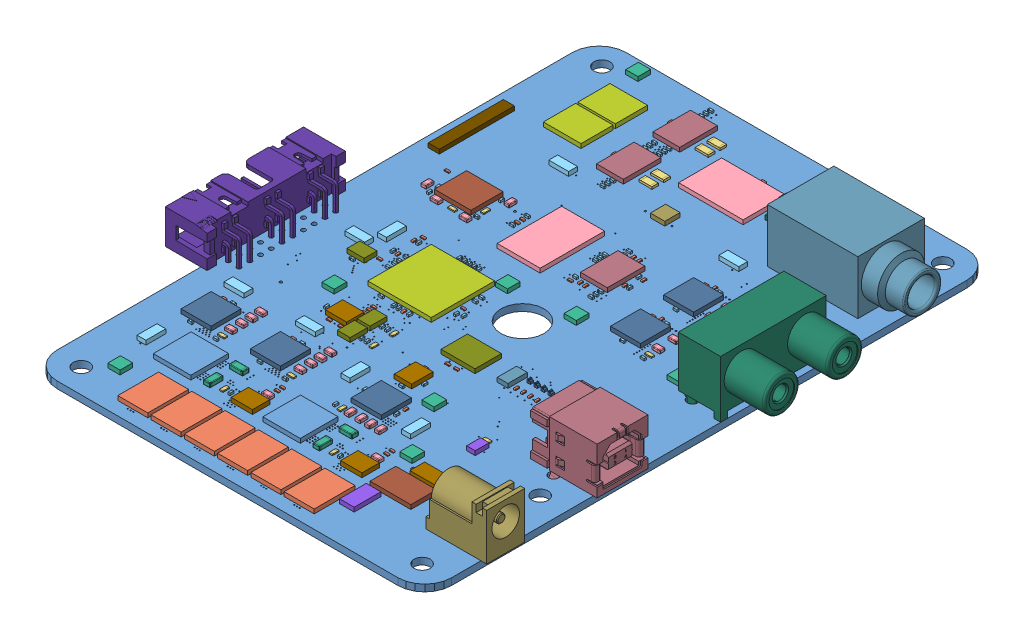
SolidWorks assembly smartstandusbdacamplifierrevb, configuration Default. Lengths in mm.
Overall size (110.75 17.47 134.62).
232 component instances, 34 part files, 16 mates.
Components (placement in the parent):
- smartstandusbdacamplifierrevb-1: smartstandusbdacamplifierrevb [Default] at origin size (93.34 1.6 134.62)
- CHEMICON_F55_CHEMICON_F55-1: CHEMICON_F55_CHEMICON_F55 [Default] at (36.83 1.6 59.309) x (0 0 1) z (0 1 0) size (9.65 7.11 1)
- CHEMICON_F55_CHEMICON_F55-2: CHEMICON_F55_CHEMICON_F55 [Default] at (52.578 1.6 59.309) x (0 0 1) z (0 1 0) size (9.65 7.11 1)
- CHEMICON_F55_CHEMICON_F55-3: CHEMICON_F55_CHEMICON_F55 [Default] at (60.452 1.6 59.309) x (0 0 1) z (0 1 0) size (9.65 7.11 1)
- CHEMICON_F55_CHEMICON_F55-4: CHEMICON_F55_CHEMICON_F55 [Default] at (28.956 1.6 59.309) x (0 0 1) z (0 1 0) size (9.65 7.11 1)
- CHEMICON_F55_CHEMICON_F55-5: CHEMICON_F55_CHEMICON_F55 [Default] at (44.704 1.6 59.309) x (0 0 1) z (0 1 0) size (9.65 7.11 1)
- CHEMICON_F55_CHEMICON_F55-6: CHEMICON_F55_CHEMICON_F55 [Default] at (21.082 1.6 59.309) x (0 0 1) z (0 1 0) size (9.65 7.11 1)
- C0603-1: C0603 [Default] at (69.596 1.6 28.829) x (-1 0 0) z (0 1 0) size (1.6 0.8 0.3)
- C0603-2: C0603 [Default] at (27.94 1.6 49.276) x (0 0 -1) z (0 1 0) size (1.6 0.8 0.3)
- C0603-3: C0603 [Default] at (33.147 1.6 38.608) x (1 0 0) z (0 1 0) size (1.6 0.8 0.3)
- C0603-4: C0603 [Default] at (53.848 1.6 49.276) x (0 0 -1) z (0 1 0) size (1.6 0.8 0.3)
- C0603-5: C0603 [Default] at (45.847 1.6 39.37) x (0 0 1) z (0 1 0) size (1.6 0.8 0.3)
- C0603-6: C0603 [Default] at (16.764 1.6 38.608) x (1 0 0) z (0 1 0) size (1.6 0.8 0.3)
- C0603-7: C0603 [Default] at (71.247 1.6 -8.001) x (1 0 0) z (0 1 0) size (1.6 0.8 0.3)
- C0603-8: C0603 [Default] at (71.247 1.6 -15.875) x (1 0 0) z (0 1 0) size (1.6 0.8 0.3)
- C0603-9: C0603 [Default] at (71.12 1.6 -20.701) x (1 0 0) z (0 1 0) size (1.6 0.8 0.3)
- C0603-10: C0603 [Default] at (71.12 1.6 -28.575) x (1 0 0) z (0 1 0) size (1.6 0.8 0.3)
- C0603-11: C0603 [Default] at (18.034 1.6 -14.605) x (-1 0 0) z (0 1 0) size (1.6 0.8 0.3)
- C0603-12: C0603 [Default] at (22.352 1.6 -18.034) x (0 0 1) z (0 1 0) size (1.6 0.8 0.3)
- C0603-13: C0603 [Default] at (36.703 1.6 22.733) x (0 0 -1) z (0 1 0) size (1.6 0.8 0.3)
- C0603-14: C0603 [Default] at (36.703 1.6 17.907) x (0 0 -1) z (0 1 0) size (1.6 0.8 0.3)
- C0805-1: C0805 [Default] at (34.544 1.6 45.593) x (-1 0 0) z (0 1 0) size (2 1.25 0.78)
- C0805-2: C0805 [Default] at (33.147 1.6 36.576) x (1 0 0) z (0 1 0) size (2 1.25 0.78)
- C0805-3: C0805 [Default] at (33.147 1.6 34.036) x (1 0 0) z (0 1 0) size (2 1.25 0.78)
- C0805-4: C0805 [Default] at (33.147 1.6 31.75) x (1 0 0) z (0 1 0) size (2 1.25 0.78)
- C0805-5: C0805 [Default] at (33.147 1.6 29.464) x (1 0 0) z (0 1 0) size (2 1.25 0.78)
- C0805-6: C0805 [Default] at (60.452 1.6 45.593) x (-1 0 0) z (0 1 0) size (2 1.25 0.78)
- C0805-7: C0805 [Default] at (47.879 1.6 39.37) x (0 0 1) z (0 1 0) size (2 1.25 0.78)
- C0805-8: C0805 [Default] at (54.991 1.6 39.37) x (0 0 1) z (0 1 0) size (2 1.25 0.78)
- C0805-9: C0805 [Default] at (52.705 1.6 39.37) x (0 0 1) z (0 1 0) size (2 1.25 0.78)
- C0805-10: C0805 [Default] at (50.419 1.6 39.37) x (0 0 1) z (0 1 0) size (2 1.25 0.78)
- C0805-11: C0805 [Default] at (16.764 1.6 36.576) x (1 0 0) z (0 1 0) size (2 1.25 0.78)
- C0805-12: C0805 [Default] at (16.764 1.6 34.036) x (1 0 0) z (0 1 0) size (2 1.25 0.78)
- C0805-13: C0805 [Default] at (16.764 1.6 31.75) x (1 0 0) z (0 1 0) size (2 1.25 0.78)
- C0805-14: C0805 [Default] at (16.764 1.6 29.464) x (1 0 0) z (0 1 0) size (2 1.25 0.78)
- C0805-15: C0805 [Default] at (71.247 1.6 -10.033) x (1 0 0) z (0 1 0) size (2 1.25 0.78)
- C0805-16: C0805 [Default] at (71.247 1.6 -13.843) x (1 0 0) z (0 1 0) size (2 1.25 0.78)
- C0805-17: C0805 [Default] at (71.12 1.6 -22.733) x (1 0 0) z (0 1 0) size (2 1.25 0.78)
- C0805-18: C0805 [Default] at (71.12 1.6 -26.543) x (1 0 0) z (0 1 0) size (2 1.25 0.78)
- C0805-19: C0805 [Default] at (10.16 1.6 -16.51) x (0 0 1) z (0 1 0) size (2 1.25 0.78)
- C0805-20: C0805 [Default] at (21.59 1.6 -14.097) x (1 0 0) z (0 1 0) size (2 1.25 0.78)
- C0805-21: C0805 [Default] at (14.478 1.6 -14.351) x (1 0 0) z (0 1 0) size (2 1.25 0.78)
- C0805-22: C0805 [Default] at (23.876 1.6 -22.479) x (0 0 -1) z (0 1 0) size (2 1.25 0.78)
- C0402-1: C0402 [Default] at (27.94 1.6 30.861) x (-1 0 0) z (0 1 0) size (1 0.5 0.5)
- C0402-2: C0402 [Default] at (29.591 1.6 49.403) x (0 0 -1) z (0 1 0) size (1 0.5 0.5)
- C0402-3: C0402 [Default] at (33.147 1.6 40.132) x (1 0 0) z (0 1 0) size (1 0.5 0.5)
- C0402-4: C0402 [Default] at (26.67 1.6 39.624) x (-1 0 0) z (0 1 0) size (1 0.5 0.5)
- C0402-5: C0402 [Default] at (53.594 1.6 34.163) x (0 0 -1) z (0 1 0) size (1 0.5 0.5)
- C0402-6: C0402 [Default] at (55.499 1.6 49.403) x (0 0 -1) z (0 1 0) size (1 0.5 0.5)
- C0402-7: C0402 [Default] at (44.323 1.6 39.37) x (0 0 1) z (0 1 0) size (1 0.5 0.5)
- C0402-8: C0402 [Default] at (44.831 1.6 32.893) x (0 0 -1) z (0 1 0) size (1 0.5 0.5)
- C0402-9: C0402 [Default] at (11.557 1.6 30.861) x (-1 0 0) z (0 1 0) size (1 0.5 0.5)
- C0402-10: C0402 [Default] at (16.764 1.6 40.132) x (1 0 0) z (0 1 0) size (1 0.5 0.5)
- C0402-11: C0402 [Default] at (10.287 1.6 39.624) x (-1 0 0) z (0 1 0) size (1 0.5 0.5)
- C0402-12: C0402 [Default] at (67.056 1.6 -16.256) x (-1 0 0) z (0 1 0) size (1 0.5 0.5)
- C0402-13: C0402 [Default] at (71.247 1.6 -6.477) x (1 0 0) z (0 1 0) size (1 0.5 0.5)
- C0402-14: C0402 [Default] at (71.247 1.6 -17.399) x (1 0 0) z (0 1 0) size (1 0.5 0.5)
- C0402-15: C0402 [Default] at (65.278 1.6 -7.62) x (-1 0 0) z (0 1 0) size (1 0.5 0.5)
- C0402-16: C0402 [Default] at (66.929 1.6 -28.956) x (-1 0 0) z (0 1 0) size (1 0.5 0.5)
- C0402-17: C0402 [Default] at (71.12 1.6 -19.177) x (1 0 0) z (0 1 0) size (1 0.5 0.5)
- C0402-18: C0402 [Default] at (71.12 1.6 -30.099) x (1 0 0) z (0 1 0) size (1 0.5 0.5)
- C0402-19: C0402 [Default] at (65.151 1.6 -20.32) x (-1 0 0) z (0 1 0) size (1 0.5 0.5)
- C0402-20: C0402 [Default] at (50.673 1.6 24.638) x (0 0 -1) z (0 1 0) size (1 0.5 0.5)
- C0402-21: C0402 [Default] at (48.387 1.6 27.813) x (1 0 0) z (0 1 0) size (1 0.5 0.5)
- C0402-22: C0402 [Default] at (22.479 1.6 3.556) x (-1 0 0) z (0 1 0) size (1 0.5 0.5)
- C0402-23: C0402 [Default] at (32.131 1.6 12.192) x (0 0 1) z (0 1 0) size (1 0.5 0.5)
- C0402-24: C0402 [Default] at (40.132 1.6 6.604) x (0 0 1) z (0 1 0) size (1 0.5 0.5)
- C0402-25: C0402 [Default] at (39.751 1.6 1.778) x (1 0 0) z (0 1 0) size (1 0.5 0.5)
- C0402-26: C0402 [Default] at (22.479 1.6 5.08) x (-1 0 0) z (0 1 0) size (1 0.5 0.5)
- C0402-27: C0402 [Default] at (30.988 1.6 12.192) x (0 0 1) z (0 1 0) size (1 0.5 0.5)
- C0402-28: C0402 [Default] at (32.512 1.6 -5.207) x (0 0 -1) z (0 1 0) size (1 0.5 0.5)
- C0402-29: C0402 [Default] at (31.369 1.6 -5.207) x (0 0 -1) z (0 1 0) size (1 0.5 0.5)
- C0402-30: C0402 [Default] at (30.226 1.6 -5.207) x (0 0 -1) z (0 1 0) size (1 0.5 0.5)
- C0402-31: C0402 [Default] at (22.479 1.6 0.889) x (-1 0 0) z (0 1 0) size (1 0.5 0.5)
- C0402-32: C0402 [Default] at (39.751 1.6 0.254) x (1 0 0) z (0 1 0) size (1 0.5 0.5)
- C0402-33: C0402 [Default] at (29.083 1.6 -5.207) x (0 0 -1) z (0 1 0) size (1 0.5 0.5)
- C0402-34: C0402 [Default] at (33.655 1.6 -5.207) x (0 0 -1) z (0 1 0) size (1 0.5 0.5)
- C0402-35: C0402 [Default] at (22.479 1.6 2.413) x (-1 0 0) z (0 1 0) size (1 0.5 0.5)
- C0402-36: C0402 [Default] at (41.402 1.6 6.096) x (0 0 1) z (0 1 0) size (1 0.5 0.5)
- C0402-37: C0402 [Default] at (27.559 1.6 11.811) x (-1 0 0) z (0 1 0) size (1 0.5 0.5)
- C0402-38: C0402 [Default] at (34.671 1.6 12.192) x (0 0 1) z (0 1 0) size (1 0.5 0.5)
- C0402-39: C0402 [Default] at (16.51 1.6 7.62) x (-1 0 0) z (0 1 0) size (1 0.5 0.5)
- C0402-40: C0402 [Default] at (19.685 1.6 1.143) x (0 0 -1) z (0 1 0) size (1 0.5 0.5)
- C0402-41: C0402 [Default] at (11.938 1.6 -17.272) x (0 0 1) z (0 1 0) size (1 0.5 0.5)
- C0402-42: C0402 [Default] at (28.448 1.6 -18.288) x (-1 0 0) z (0 1 0) size (1 0.5 0.5)
- C0402-43: C0402 [Default] at (28.448 1.6 -21.844) x (-1 0 0) z (0 1 0) size (1 0.5 0.5)
- C0402-44: C0402 [Default] at (22.606 1.6 -15.748) x (1 0 0) z (0 1 0) size (1 0.5 0.5)
- C0402-45: C0402 [Default] at (11.938 1.6 -15.24) x (0 0 1) z (0 1 0) size (1 0.5 0.5)
- C0402-46: C0402 [Default] at (22.098 1.6 -22.098) x (0 0 -1) z (0 1 0) size (1 0.5 0.5)
- C0402-47: C0402 [Default] at (46.609 1.6 -15.113) x (-1 0 0) z (0 1 0) size (1 0.5 0.5)
- C0402-48: C0402 [Default] at (55.245 1.6 -19.304) x (0 0 1) z (0 1 0) size (1 0.5 0.5)
- C0402-49: C0402 [Default] at (47.752 1.6 -26.67) x (-1 0 0) z (0 1 0) size (1 0.5 0.5)
- C0402-50: C0402 [Default] at (54.102 1.6 -22.606) x (0 0 -1) z (0 1 0) size (1 0.5 0.5)
- C0402-51: C0402 [Default] at (52.578 1.6 -12.827) x (1 0 0) z (0 1 0) size (1 0.5 0.5)
- C0402-52: C0402 [Default] at (52.578 1.6 -13.97) x (1 0 0) z (0 1 0) size (1 0.5 0.5)
- C0402-53: C0402 [Default] at (52.578 1.6 -15.113) x (1 0 0) z (0 1 0) size (1 0.5 0.5)
- C0402-54: C0402 [Default] at (45.593 1.6 -23.114) x (-1 0 0) z (0 1 0) size (1 0.5 0.5)
- C0402-55: C0402 [Default] at (45.593 1.6 -21.971) x (-1 0 0) z (0 1 0) size (1 0.5 0.5)
- C0402-56: C0402 [Default] at (45.593 1.6 -20.828) x (-1 0 0) z (0 1 0) size (1 0.5 0.5)
- C0402-57: C0402 [Default] at (28.575 1.6 -65.151) x (1 0 0) z (0 1 0) size (1 0.5 0.5)
- C0402-58: C0402 [Default] at (28.575 1.6 -64.008) x (1 0 0) z (0 1 0) size (1 0.5 0.5)
- C0402-59: C0402 [Default] at (28.575 1.6 -62.865) x (1 0 0) z (0 1 0) size (1 0.5 0.5)
- C0402-60: C0402 [Default] at (28.448 1.6 -51.943) x (1 0 0) z (0 1 0) size (1 0.5 0.5)
- C0402-61: C0402 [Default] at (28.448 1.6 -50.8) x (1 0 0) z (0 1 0) size (1 0.5 0.5)
- C0402-62: C0402 [Default] at (28.448 1.6 -49.657) x (1 0 0) z (0 1 0) size (1 0.5 0.5)
- C0402-63: C0402 [Default] at (31.369 1.6 -50.165) x (-1 0 0) z (0 1 0) size (1 0.5 0.5)
- C0402-64: C0402 [Default] at (31.369 1.6 -51.308) x (-1 0 0) z (0 1 0) size (1 0.5 0.5)
- C0402-65: C0402 [Default] at (31.369 1.6 -52.451) x (-1 0 0) z (0 1 0) size (1 0.5 0.5)
- C0402-66: C0402 [Default] at (31.242 1.6 -36.957) x (-1 0 0) z (0 1 0) size (1 0.5 0.5)
- C0402-67: C0402 [Default] at (31.242 1.6 -38.1) x (-1 0 0) z (0 1 0) size (1 0.5 0.5)
- C0402-68: C0402 [Default] at (31.242 1.6 -39.243) x (-1 0 0) z (0 1 0) size (1 0.5 0.5)
- C0402-69: C0402 [Default] at (35.179 1.6 22.733) x (0 0 -1) z (0 1 0) size (1 0.5 0.5)
- C0402-70: C0402 [Default] at (33.909 1.6 22.733) x (0 0 -1) z (0 1 0) size (1 0.5 0.5)
- C0402-71: C0402 [Default] at (35.179 1.6 17.907) x (0 0 -1) z (0 1 0) size (1 0.5 0.5)
- C0402-72: C0402 [Default] at (33.909 1.6 17.907) x (0 0 -1) z (0 1 0) size (1 0.5 0.5)
- C0402-73: C0402 [Default] at (23.241 1.6 20.447) x (0 0 1) z (0 1 0) size (1 0.5 0.5)
- C0402-74: C0402 [Default] at (21.082 1.6 -3.556) x (0 0 -1) z (0 1 0) size (1 0.5 0.5)
- C1206-1: C1206 [Default] at (25.146 1.6 49.149) x (0 0 -1) z (0 1 0) size (3.2 1.6 1)
- C1206-2: C1206 [Default] at (25.781 1.6 43.688) x (1 0 0) z (0 1 0) size (3.2 1.6 1)
- C1206-3: C1206 [Default] at (51.054 1.6 49.149) x (0 0 -1) z (0 1 0) size (3.2 1.6 1)
- C1206-4: C1206 [Default] at (51.689 1.6 43.688) x (1 0 0) z (0 1 0) size (3.2 1.6 1)
- KEMET5MM6_07_2_KEMET5MM6_07_2-1: KEMET5MM6_07_2_KEMET5MM6_07_2 [Default] at (16.256 1.6 -54.229) x (1 0 0) z (0 1 0) size (8.89 7.62 1)
- KEMET5MM6_07_2_KEMET5MM6_07_2-2: KEMET5MM6_07_2_KEMET5MM6_07_2 [Default] at (16.256 1.6 -46.101) x (1 0 0) z (0 1 0) size (8.89 7.62 1)
- SOD128_5A-1: SOD128_5A [Default] at (66.675 1.6 55.88) x (0 0 -1) z (0 1 0) size (6.33 3.46 1)
- SMA_13_6V-1: SMA_13_6V [Default] at (70.993 1.6 43.18) x (-1 0 0) z (0 1 0) size (7.1 3.5 1)
- DIALIGHT-0603-1: DIALIGHT-0603 [Default] at (62.357 1.6 11.684) x (0 0 1) z (0 1 0) size (0.79 0.72 1.63)
- DIALIGHT-0603-2: DIALIGHT-0603 [Default] at (68.961 1.6 11.684) x (0 0 1) z (0 1 0) size (0.79 0.72 1.63)
- DIALIGHT-0603-3: DIALIGHT-0603 [Default] at (70.612 1.6 11.684) x (0 0 1) z (0 1 0) size (0.79 0.72 1.63)
- DIALIGHT-0603-4: DIALIGHT-0603 [Default] at (67.31 1.6 11.684) x (0 0 1) z (0 1 0) size (0.79 0.72 1.63)
- DIALIGHT-0603-5: DIALIGHT-0603 [Default] at (65.659 1.6 11.684) x (0 0 1) z (0 1 0) size (0.79 0.72 1.63)
- DIALIGHT-0603-6: DIALIGHT-0603 [Default] at (64.008 1.6 11.684) x (0 0 1) z (0 1 0) size (0.79 0.72 1.63)
- 2920L_0_6A-1: 2920L_0_6A [Default] at (69.723 1.6 48.768) x (-1 0 0) z (0 1 0) size (9.65 6.1 1)
- PJ002A_PJ002A-1: PJ002A_PJ002A [Default] at (94.695 8.1 49.51) size (14.4 14.5 9.4)
- 292304-1: 292304 [Default] at (94.665 7.29 21.844) x (0 0 -1) z (1 0 0) size (14.36 15.42 15.7)
- NRJ6HH_NRJ6HH-1: NRJ6HH_NRJ6HH [Default] at (88.32 1.6 -46.61) x (0 0 -1) z (1 0 0) size (15.75 16.7 33.2)
- PJRAN2X1U01AUX-1: PJRAN2X1U01AUX [Default] at (88.289 9.0803 -15.2344) x (0 0 -1) z (0 -1 0) size (25 19.5 17.47)
- T1MSINGLE5POS_T1M5POS-1: T1MSINGLE5POS_T1M5POS [Default] at (50.292 1.6 12.573) x (1 0 0) z (0 1 0) size (8.03 6.25 1)
- N2520-5002-1: N2520-5002 [Default] at (1.4342 7.3912 28.8324) x (0 1 0) z (-1 0 0) size (12.62 32.72 12.87)
- 1X07_JP3_1X07-1: 1X07_JP3_1X07 [Default] at (3.81 1.6 -33.274) x (0 0 -1) z (1 0 0) size (17.78 1 2.62)
- TDKVLP8040_TDKVLP8040-1: TDKVLP8040_TDKVLP8040 [Default] at (17.526 1.6 46.863) x (0 0 1) z (0 1 0) size (8.93 8.86 1)
- TDKVLP8040_TDKVLP8040-2: TDKVLP8040_TDKVLP8040 [Default] at (43.434 1.6 46.863) x (0 0 1) z (0 1 0) size (8.93 8.86 1)
- R0402-1: R0402 [Default] at (39.751 1.6 4.572) x (-1 0 0) z (0 1 0) size (1.01 0.5 0.32)
- R0402-2: R0402 [Default] at (25.781 1.6 30.861) x (-1 0 0) z (0 1 0) size (1.01 0.5 0.32)
- R0402-3: R0402 [Default] at (34.544 1.6 42.164) x (-1 0 0) z (0 1 0) size (1.01 0.5 0.32)
- R0402-4: R0402 [Default] at (34.544 1.6 43.434) x (1 0 0) z (0 1 0) size (1.01 0.5 0.32)
- R0402-5: R0402 [Default] at (53.594 1.6 32.004) x (0 0 -1) z (0 1 0) size (1.01 0.5 0.32)
- R0402-6: R0402 [Default] at (60.452 1.6 42.164) x (-1 0 0) z (0 1 0) size (1.01 0.5 0.32)
- R0402-7: R0402 [Default] at (60.452 1.6 43.434) x (1 0 0) z (0 1 0) size (1.01 0.5 0.32)
- R0402-8: R0402 [Default] at (9.398 1.6 30.861) x (-1 0 0) z (0 1 0) size (1.01 0.5 0.32)
- R0402-9: R0402 [Default] at (65.405 1.6 -16.637) x (0 0 -1) z (0 1 0) size (1.01 0.5 0.32)
- R0402-10: R0402 [Default] at (63.754 1.6 -16.256) x (1 0 0) z (0 1 0) size (1.01 0.5 0.32)
- R0402-11: R0402 [Default] at (65.278 1.6 -29.337) x (0 0 -1) z (0 1 0) size (1.01 0.5 0.32)
- R0402-12: R0402 [Default] at (63.627 1.6 -28.956) x (1 0 0) z (0 1 0) size (1.01 0.5 0.32)
- R0402-13: R0402 [Default] at (47.498 1.6 21.209) x (1 0 0) z (0 1 0) size (1.01 0.5 0.32)
- R0402-14: R0402 [Default] at (20.828 1.6 1.143) x (0 0 -1) z (0 1 0) size (1.01 0.5 0.32)
- R0402-15: R0402 [Default] at (19.685 1.6 4.318) x (1 0 0) z (0 1 0) size (1.01 0.5 0.32)
- R0402-16: R0402 [Default] at (33.274 1.6 12.192) x (0 0 1) z (0 1 0) size (1.01 0.5 0.32)
- R0402-17: R0402 [Default] at (51.308 1.6 17.78) x (1 0 0) z (0 1 0) size (1.01 0.5 0.32)
- R0402-18: R0402 [Default] at (49.276 1.6 17.78) x (-1 0 0) z (0 1 0) size (1.01 0.5 0.32)
- R0402-19: R0402 [Default] at (28.829 1.6 14.859) x (-1 0 0) z (0 1 0) size (1.01 0.5 0.32)
- R0402-20: R0402 [Default] at (28.829 1.6 16.002) x (-1 0 0) z (0 1 0) size (1.01 0.5 0.32)
- R0402-21: R0402 [Default] at (9.652 1.6 -21.717) x (-1 0 0) z (0 1 0) size (1.01 0.5 0.32)
- R0402-22: R0402 [Default] at (28.448 1.6 -19.431) x (1 0 0) z (0 1 0) size (1.01 0.5 0.32)
- R0402-23: R0402 [Default] at (28.448 1.6 -20.701) x (1 0 0) z (0 1 0) size (1.01 0.5 0.32)
- R0402-24: R0402 [Default] at (48.26 1.6 -14.605) x (0 0 -1) z (0 1 0) size (1.01 0.5 0.32)
- R0402-25: R0402 [Default] at (46.609 1.6 -13.843) x (1 0 0) z (0 1 0) size (1.01 0.5 0.32)
- R0402-26: R0402 [Default] at (54.102 1.6 -19.304) x (0 0 1) z (0 1 0) size (1.01 0.5 0.32)
- R0402-27: R0402 [Default] at (49.403 1.6 -26.035) x (0 0 1) z (0 1 0) size (1.01 0.5 0.32)
- R0402-28: R0402 [Default] at (47.752 1.6 -25.527) x (1 0 0) z (0 1 0) size (1.01 0.5 0.32)
- R0402-29: R0402 [Default] at (55.245 1.6 -22.606) x (0 0 -1) z (0 1 0) size (1.01 0.5 0.32)
- R0402-30: R0402 [Default] at (49.53 1.6 -14.605) x (0 0 1) z (0 1 0) size (1.01 0.5 0.32)
- R0402-31: R0402 [Default] at (50.8 1.6 -26.035) x (0 0 1) z (0 1 0) size (1.01 0.5 0.32)
- R0402-32: R0402 [Default] at (26.035 1.6 -58.166) x (0 0 1) z (0 1 0) size (1.01 0.5 0.32)
- R0402-33: R0402 [Default] at (25.908 1.6 -44.958) x (0 0 1) z (0 1 0) size (1.01 0.5 0.32)
- R0402-34: R0402 [Default] at (28.829 1.6 22.733) x (1 0 0) z (0 1 0) size (1.01 0.5 0.32)
- R0402-35: R0402 [Default] at (28.829 1.6 17.145) x (1 0 0) z (0 1 0) size (1.01 0.5 0.32)
- R0402-36: R0402 [Default] at (26.162 1.6 22.733) x (-1 0 0) z (0 1 0) size (1.01 0.5 0.32)
- R0402-37: R0402 [Default] at (20.447 1.6 -5.207) x (1 0 0) z (0 1 0) size (1.01 0.5 0.32)
- R0402-38: R0402 [Default] at (49.276 1.6 -56.896) x (-1 0 0) z (0 1 0) size (1.01 0.5 0.32)
- R0402-39: R0402 [Default] at (19.939 1.6 -3.556) x (0 0 1) z (0 1 0) size (1.01 0.5 0.32)
- R0402-40: R0402 [Default] at (62.357 1.6 14.605) x (0 0 -1) z (0 1 0) size (1.01 0.5 0.32)
- R0402-41: R0402 [Default] at (68.961 1.6 14.605) x (0 0 -1) z (0 1 0) size (1.01 0.5 0.32)
- R0402-42: R0402 [Default] at (70.612 1.6 14.605) x (0 0 -1) z (0 1 0) size (1.01 0.5 0.32)
- R0402-43: R0402 [Default] at (67.31 1.6 14.605) x (0 0 -1) z (0 1 0) size (1.01 0.5 0.32)
- R0402-44: R0402 [Default] at (65.659 1.6 14.605) x (0 0 -1) z (0 1 0) size (1.01 0.5 0.32)
- R0402-45: R0402 [Default] at (64.008 1.6 14.605) x (0 0 -1) z (0 1 0) size (1.01 0.5 0.32)
- R1206-1: R1206 [Default] at (36.068 1.6 -56.261) x (1 0 0) z (0 1 0) size (3.1 1.55 0.55)
- R1206-2: R1206 [Default] at (36.068 1.6 -59.055) x (1 0 0) z (0 1 0) size (3.1 1.55 0.55)
- R1206-3: R1206 [Default] at (35.941 1.6 -43.053) x (1 0 0) z (0 1 0) size (3.1 1.55 0.55)
- R1206-4: R1206 [Default] at (35.941 1.6 -45.847) x (1 0 0) z (0 1 0) size (3.1 1.55 0.55)
- TQ2_TQ212V-1: TQ2_TQ212V [Default] at (36.322 1.6 -19.558) x (0 0 1) z (0 1 0) size (15.24 10.16 1)
- TQ2_TQ212V-2: TQ2_TQ212V [Default] at (47.879 1.6 -50.927) x (-1 0 0) z (0 1 0) size (15.24 10.16 1)
- TESTPOINT1_5WITHGND_TESTPOINTWITHGND-1: TESTPOINT1_5WITHGND_TESTPOINTWITHGND [Default] at (12.954 1.6 2.413) x (-1 0 0) z (0 1 0) size (4.7 2.1 1)
- TESTPOINT1_5WITHGND_TESTPOINTWITHGND-2: TESTPOINT1_5WITHGND_TESTPOINTWITHGND [Default] at (58.928 1.6 -62.357) x (-1 0 0) z (0 1 0) size (4.7 2.1 1)
- TESTPOINT1_5WITHGND_TESTPOINTWITHGND-3: TESTPOINT1_5WITHGND_TESTPOINTWITHGND [Default] at (8.509 1.6 47.117) x (0 0 -1) z (0 1 0) size (4.7 2.1 1)
- TESTPOINT1_5WITHGND_TESTPOINTWITHGND-4: TESTPOINT1_5WITHGND_TESTPOINTWITHGND [Default] at (15.875 1.6 -2.413) x (0 0 -1) z (0 1 0) size (4.7 2.1 1)
- TESTPOINT1_5WITHGND_TESTPOINTWITHGND-5: TESTPOINT1_5WITHGND_TESTPOINTWITHGND [Default] at (9.144 1.6 27.178) x (-1 0 0) z (0 1 0) size (4.7 2.1 1)
- TESTPOINT1_5WITHGND_TESTPOINTWITHGND-6: TESTPOINT1_5WITHGND_TESTPOINTWITHGND [Default] at (25.527 1.6 26.67) x (-1 0 0) z (0 1 0) size (4.7 2.1 1)
- TESTPOINT1_5WITHGND_TESTPOINTWITHGND-7: TESTPOINT1_5WITHGND_TESTPOINTWITHGND [Default] at (40.386 1.6 30.734) x (0 0 -1) z (0 1 0) size (4.7 2.1 1)
- TESTPOINT1_5WITHGND_TESTPOINTWITHGND-8: TESTPOINT1_5WITHGND_TESTPOINTWITHGND [Default] at (59.055 1.6 35.052) x (0 0 -1) z (0 1 0) size (4.7 2.1 1)
- TESTPOINT1_5WITHGND_TESTPOINTWITHGND-9: TESTPOINT1_5WITHGND_TESTPOINTWITHGND [Default] at (22.606 1.6 -36.195) x (-1 0 0) z (0 1 0) size (4.7 2.1 1)
- TESTPOINT1_5WITHGND_TESTPOINTWITHGND-10: TESTPOINT1_5WITHGND_TESTPOINTWITHGND [Default] at (62.23 1.6 -36.83) x (-1 0 0) z (0 1 0) size (4.7 2.1 1)
- FIDUCIAL_1MM_FIDUCIAL1MM-1: FIDUCIAL_1MM_FIDUCIAL1MM [Default] at (12.319 1.6 -64.262) size (2.9 1 3)
- FIDUCIAL_1MM_FIDUCIAL1MM-2: FIDUCIAL_1MM_FIDUCIAL1MM [Default] at (54.991 1.6 -6.985) size (2.9 1 3)
- FIDUCIAL_1MM_FIDUCIAL1MM-3: FIDUCIAL_1MM_FIDUCIAL1MM [Default] at (40.386 1.6 -5.334) size (2.9 1 3)
- FIDUCIAL_1MM_FIDUCIAL1MM-4: FIDUCIAL_1MM_FIDUCIAL1MM [Default] at (11.176 1.6 57.15) size (2.9 1 3)
- FIDUCIAL_1MM_FIDUCIAL1MM-5: FIDUCIAL_1MM_FIDUCIAL1MM [Default] at (79.756 1.6 -6.604) size (2.9 1 3)
- FIDUCIAL_1MM_FIDUCIAL1MM-6: FIDUCIAL_1MM_FIDUCIAL1MM [Default] at (63.881 1.6 40.767) size (2.9 1 3)
- FIDUCIAL_1MM_FIDUCIAL1MM-7: FIDUCIAL_1MM_FIDUCIAL1MM [Default] at (19.939 1.6 15.24) size (2.9 1 3)
- FIDUCIAL_1MM_FIDUCIAL1MM-8: FIDUCIAL_1MM_FIDUCIAL1MM [Default] at (55.88 1.6 27.559) size (2.9 1 3)
- TQFP64EXPOSEDPAD_XUF208256TQ64-1: TQFP64EXPOSEDPAD_XUF208256TQ64 [Default] at (31.115 1.6 3.556) x (1 0 0) z (0 1 0) size (15 15 1)
- RPUSONN10_TPD4E02B04DQA-1: RPUSONN10_TPD4E02B04DQA [Default] at (70.104 1.6 31.369) x (0 0 -1) z (0 1 0) size (3.3 2.03 1)
- RPDSOG6DBV_TS5A3159DBV-1: RPDSOG6DBV_TS5A3159DBV [Default] at (33.782 1.6 49.022) x (0 0 1) z (0 1 0) size (4.13 5.06 1)
- RPDSOG6DBV_TS5A3159DBV-2: RPDSOG6DBV_TS5A3159DBV [Default] at (59.69 1.6 49.022) x (0 0 1) z (0 1 0) size (4.13 5.06 1)
- SPVQFNN20_TPS7A3301RGW-1: SPVQFNN20_TPS7A3301RGW [Default] at (27.178 1.6 35.306) x (-1 0 0) z (0 1 0) size (7.11 7.11 1)
- SPVQFNN20_TPS7A3301RGW-2: SPVQFNN20_TPS7A3301RGW [Default] at (49.149 1.6 33.401) x (0 0 -1) z (0 1 0) size (7.11 7.11 1)
- SPVQFNN20_TPS7A3301RGW-3: SPVQFNN20_TPS7A3301RGW [Default] at (10.795 1.6 35.306) x (-1 0 0) z (0 1 0) size (7.11 7.11 1)
- SPVQFNN20_TPS7A3301RGW-4: SPVQFNN20_TPS7A3301RGW [Default] at (65.151 1.6 -11.938) x (-1 0 0) z (0 1 0) size (7.11 7.11 1)
- SPVQFNN20_TPS7A3301RGW-5: SPVQFNN20_TPS7A3301RGW [Default] at (65.024 1.6 -24.638) x (-1 0 0) z (0 1 0) size (7.11 7.11 1)
- RPDSOG6DBV_TS5A3159DBV-3: RPDSOG6DBV_TS5A3159DBV [Default] at (47.879 1.6 24.511) x (1 0 0) z (0 1 0) size (4.13 5.06 1)
- RPDSOG20_PCM5102A-1: RPDSOG20_PCM5102A [Default] at (17.018 1.6 -19.431) x (0 0 -1) z (0 1 0) size (7.62 8.64 1)
- SOT457_SZNUD3124-1: SOT457_SZNUD3124 [Default] at (44.831 1.6 -38.1) x (-1 0 0) z (0 1 0) size (3.41 3.62 1)
- DMP8_NJM4556AM-1: DMP8_NJM4556AM [Default] at (50.165 1.6 -20.32) x (-1 0 0) z (0 1 0) size (6.35 8.89 1)
- DMP8_NJM4556AM-2: DMP8_NJM4556AM [Default] at (29.972 1.6 -57.658) x (1 0 0) z (0 1 0) size (6.35 8.89 1)
- DMP8_NJM4556AM-3: DMP8_NJM4556AM [Default] at (29.845 1.6 -44.45) x (1 0 0) z (0 1 0) size (6.35 8.89 1)
- RPDSOG6DBV_TS5A3159DBV-4: RPDSOG6DBV_TS5A3159DBV [Default] at (27.051 1.6 19.939) x (0 0 -1) z (0 1 0) size (4.13 5.06 1)
- RPDSOG8DCU_SN74LVC3G34DCU-1: RPDSOG8DCU_SN74LVC3G34DCU [Default] at (59.944 1.6 13.208) x (1 0 0) z (0 1 0) size (2.54 4.57 1)
- RPDSOG3_TPD2E007DCK-1: RPDSOG3_TPD2E007DCK [Default] at (58.674 1.6 -50.8) x (0 0 1) z (0 1 0) size (2.61 3.25 1)
- RPDSOG3_TPD2E007DCK-2: RPDSOG3_TPD2E007DCK [Default] at (77.597 1.6 -33.528) x (0 0 1) z (0 1 0) size (2.61 3.25 1)
- KC2520C_24_576MHZ-1: KC2520C_24_576MHZ [Default] at (16.51 1.6 5.334) x (1 0 0) z (0 1 0) size (4.06 3.05 1)
- KC2520C_24_576MHZ-2: KC2520C_24_576MHZ [Default] at (31.623 1.6 22.733) x (0 0 -1) z (0 1 0) size (4.06 3.05 1)
- KC2520C_24_576MHZ-3: KC2520C_24_576MHZ [Default] at (31.623 1.6 18.034) x (0 0 -1) z (0 1 0) size (4.06 3.05 1)
Mates (geometry in assembly coordinates):
- Coincident1: coincident anti-aligned: plane of smartstandusbdacamplifierrevb-1 through (0 1.6 0) normal (0 1 0); plane of PJ002A_PJ002A-1 through (80.295 1.6 54.01) normal (0 -1 0)
- Distance1: distance = 1.35 mm aligned: plane of PJ002A_PJ002A-1 through (94.695 1.6 54.01) normal (1 0 0); plane of smartstandusbdacamplifierrevb-1 through (93.345 1.6 -60.96) normal (1 0 0)
- Distance2: distance = 13.3 mm aligned: plane of PJ002A_PJ002A-1 through (80.295 12.6 54.01) normal (0 0 1); plane of smartstandusbdacamplifierrevb-1 through (86.995 1.6 67.31) normal (0 0 1)
- Coincident4: coincident anti-aligned: plane of smartstandusbdacamplifierrevb-1 through (0 1.6 0) normal (0 1 0); plane of 292304-1 through (94.665 1.6 21.844) normal (0 -1 0)
- Distance3: distance = 1.32 mm aligned: plane of 292304-1 through (94.665 7.29 21.844) normal (1 0 0); plane of smartstandusbdacamplifierrevb-1 through (93.345 1.6 -60.96) normal (1 0 0)
- Coincident6: coincident anti-aligned: plane of smartstandusbdacamplifierrevb-1 through (0 1.6 0) normal (0 1 0); plane of PJRAN2X1U01AUX-1 through (88.289 1.6 -15.2344) normal (0 -1 0)
- Parallel1: parallel aligned: plane of smartstandusbdacamplifierrevb-1 through (93.345 1.6 -60.96) normal (1 0 0); plane of PJRAN2X1U01AUX-1 through (93.289 9.0803 -15.2344) normal (1 0 0)
- Distance4: distance = 39.575 mm aligned: plane of PJRAN2X1U01AUX-1 through (88.289 9.0803 -27.735) normal (0 0 -1); plane of smartstandusbdacamplifierrevb-1 through (6.35 1.6 -67.31) normal (0 0 -1)
- Coincident9: coincident anti-aligned: plane of smartstandusbdacamplifierrevb-1 through (0 1.6 0) normal (0 1 0); plane of NRJ6HH_NRJ6HH-1 through (88.32 1.6 -46.61) normal (0 -1 0)
- Concentric1: concentric anti-aligned: circle of smartstandusbdacamplifierrevb-1; circle of NRJ6HH_NRJ6HH-1
- Concentric2: concentric anti-aligned: circle of smartstandusbdacamplifierrevb-1; circle of NRJ6HH_NRJ6HH-1
- Parallel3: parallel: plane of smartstandusbdacamplifierrevb-1 through (0 1.6 0) normal (0 1 0); plane of N2520-5002-1 through (-3.5569 2.0572 8.5124) normal (0 -1 0)
- Parallel4: parallel: plane of smartstandusbdacamplifierrevb-1 through (0 1.6 60.96) normal (-1 0 0); plane of N2520-5002-1 through (-7.9638 2.0572 11.0524) normal (-1 0 0)
- Tangent2: tangent: plane of smartstandusbdacamplifierrevb-1 through (0 1.6 0) normal (0 1 0); cylinder of N2520-5002-1 through (-7.9638 2.0572 11.0524) axis (1 0 0) radius 0.4572
- Distance5: distance = 0.85 mm: plane of N2520-5002-1 through (0.85 2.0572 11.0524) normal (1 0 0); plane of smartstandusbdacamplifierrevb-1 through (0 1.6 60.96) normal (-1 0 0)
- Distance6: distance = 39.9 mm aligned: plane of N2520-5002-1 through (-3.5569 2.0572 27.41) normal (0 0 1); plane of smartstandusbdacamplifierrevb-1 through (86.995 1.6 67.31) normal (0 0 1)
